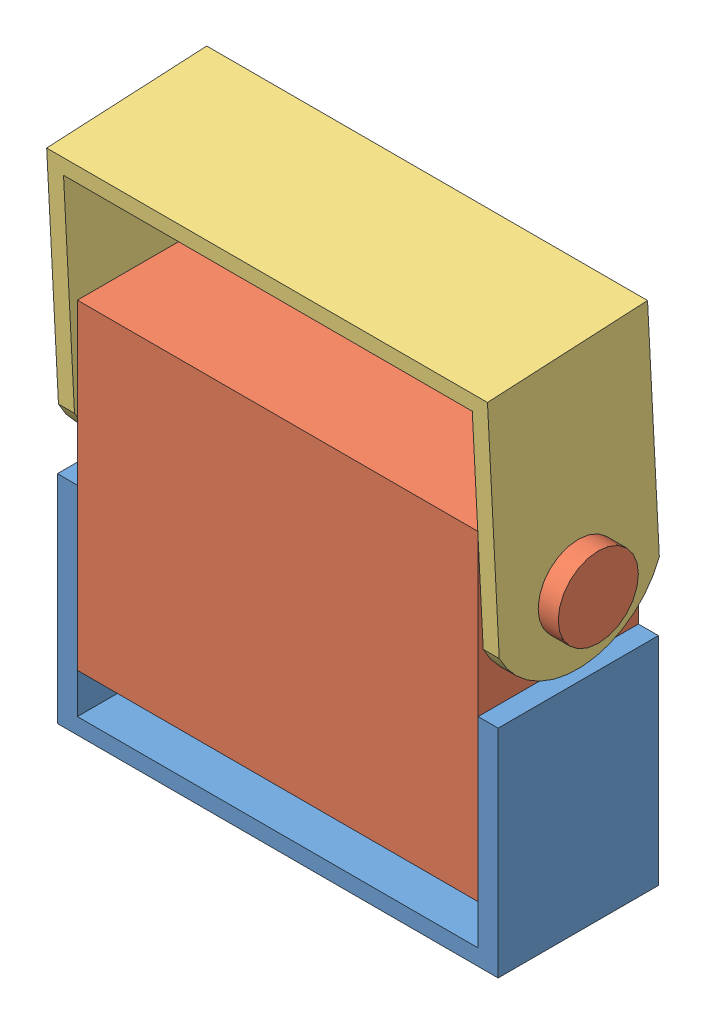
SolidWorks assembly Assem6, configuration Default. Lengths in mm.
Overall size (60 63.89 21.78).
4 component instances, 3 part files, 1 mates.
Components (placement in the parent):
- servo-3: servo [Default] at (24.0226 8.2481 66.2847) size (60 63.89 21.78)
  - servo2-1: servo2 [Default] at (27.3376 20.2914 44.339) size (55 27 20)
  - servo3-1: servo3 [Default] at (27.3376 47.2914 34.339) size (60 40 20)
  - servo1-1: servo1 [Default] at (27.3376 83.6644 45.6831) x (1 0 0) z (0 -0.051695 0.998663) size (55 35 20)
Mates (geometry in assembly coordinates):
- Lock1: lock: unknown of servo-3/servo2-1
